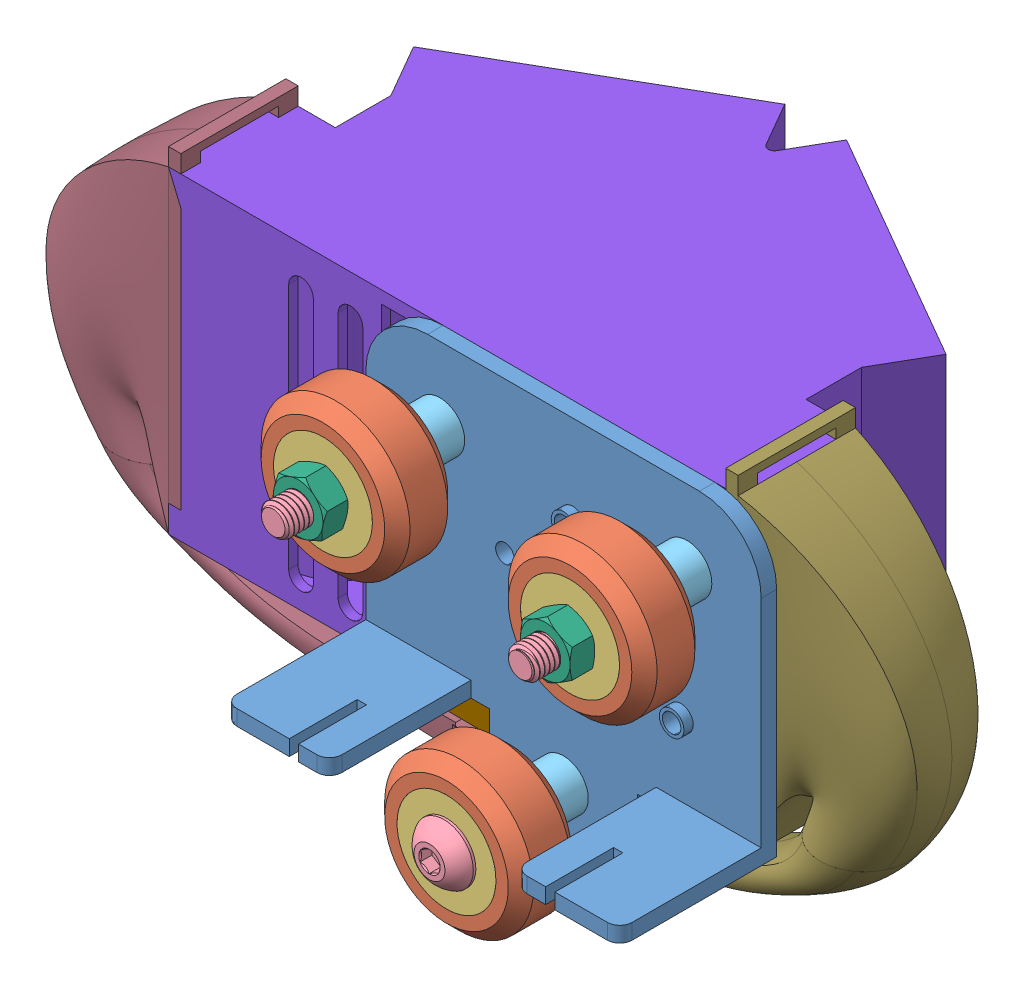
SolidWorks assembly Hot end, configuration Default. Lengths in mm.
Overall size (144.88 70.51 88.23).
31 component instances, 13 part files, 20 mates.
Components (placement in the parent):
- extruder_x_assembly-1: extruder_x_assembly [Default] at origin size (67.79 70.29 37.68)
  - E-Plate (Hot end plate)-1: E-Plate (Hot end plate) [Default] at origin size (64 64.1 29.9)
  - roller_screw_assembly-4: roller_screw_assembly [2.5mm_gap] at (20 11.85 15.1) x (-1 0 0) z (0 0 -1) size (24.1 24.1 32.32)
    - roller_rubber-1: roller_rubber [Default] at origin size (24.1 24.1 10.2)
    - Bearing for Roller-1: Bearing for Roller [Default] at (0 0 3.1) x (0.970422 -0.241413 0) z (0 0 1) size (16 16 2)
    - Bearing for Roller-2: Bearing for Roller [Default] at (0 0 -5.1) x (0.995973 0.089651 0) z (0 0 1) size (16 16 2)
    - 92095A211_Button Head Hex Drive Screw-1: 92095A211_Button Head Hex Drive Screw [92095A211] at (0 0 19.1) x (-0.966026 0.258445 0) z (0 0 1) size (9.5 9.5 32.49)
    - Roller Spacer-1: Roller Spacer [long] at (0 0 5.1) x (0.816952 -0.576706 0) z (0 0 1) size (8 8 8.75)
  - roller_screw_assembly-5: roller_screw_assembly [2.5mm_gap] at (-20 11.85 15.1) x (0.382683 -0.92388 0) z (0 0 -1) size (24.1 24.1 32.32)
    - roller_rubber-1: roller_rubber [Default] at origin size (24.1 24.1 10.2)
    - Bearing for Roller-1: Bearing for Roller [Default] at (0 0 3.1) x (0.970422 -0.241413 0) z (0 0 1) size (16 16 2)
    - Bearing for Roller-2: Bearing for Roller [Default] at (0 0 -5.1) x (0.995973 0.089651 0) z (0 0 1) size (16 16 2)
    - 92095A211_Button Head Hex Drive Screw-1: 92095A211_Button Head Hex Drive Screw [92095A211] at (0 0 19.1) x (-0.966026 0.258445 0) z (0 0 1) size (9.5 9.5 32.49)
    - Roller Spacer-1: Roller Spacer [long] at (0 0 5.1) x (0.816952 -0.576706 0) z (0 0 1) size (8 8 8.75)
  - roller_screw_assembly-6: roller_screw_assembly [normal] at (0 -28.35 15.1) x (0.97681 0.214109 0) z (0 0 1) size (24.1 24.1 32.32)
    - roller_rubber-1: roller_rubber [Default] at origin size (24.1 24.1 10.2)
    - Bearing for Roller-1: Bearing for Roller [Default] at (0 0 3.1) x (0.970422 -0.241413 0) z (0 0 1) size (16 16 2)
    - Bearing for Roller-2: Bearing for Roller [Default] at (0 0 -5.1) x (0.995973 0.089651 0) z (0 0 1) size (16 16 2)
    - 92095A211_Button Head Hex Drive Screw-1: 92095A211_Button Head Hex Drive Screw [92095A211] at (0 0 7.85) x (-0.966026 0.258445 0) z (0 0 1) size (9.5 9.5 32.49)
    - Roller Spacer-1: Roller Spacer [long] at (0 0 -13.85) x (0.816952 -0.576706 0) z (0 0 1) size (8 8 8.75)
  - 91828A241_18-8 Stainless Steel Hex Nut-4: 91828A241_18-8 Stainless Steel Hex Nut [91828A241] at (0 -28.35 -3.25) x (0.27421 -0.96167 0) z (0 0 1) size (8 9.24 4.46)
  - 91828A241_18-8 Stainless Steel Hex Nut-5: 91828A241_18-8 Stainless Steel Hex Nut [91828A241] at (20 11.85 22.2) size (8 9.24 4.46)
  - 91828A241_18-8 Stainless Steel Hex Nut-6: 91828A241_18-8 Stainless Steel Hex Nut [91828A241] at (-20 11.85 22.2) x (0.983363 -0.181649 0) z (0 0 1) size (8 9.24 4.46)
- radiator-1: radiator [Default] at (-16.5 -10.6 -11.75) size (20 27.8 12.17)
- blower-1: blower [Default] at (-20.3443 -2 -26.25) x (-1 0 0) z (0 0 -1) size (92.21 51.5 58.66)
- heatBlock-1: heatBlock [Default] at (-16.4651 -24.5 -15.7498) x (-0.999962 0 -0.008727) z (0.008727 0 -0.999962) size (20 10 20)
- nozzle-1: nozzle [Default] at (-16.5 -43.5 -11.75) x (1 0 0.000361) z (-0.000361 0 1) size (7.5 12.42 6)
- 40mm_10mm_fan-1: 40mm_10mm_fan [1939K43] at (3.4402 -5.75 -49.065) x (0.866025 0 0.5) z (-0.5 0 0.866025) size (40 40 10.64)
- 40mm_10mm_fan-2: 40mm_10mm_fan [1939K43] at (-44.3969 -5.75 -48.9103) x (0.866025 0 -0.5) z (0.5 0 0.866025) size (40 40 10.64)
- loftTesrtleft-1: loftTesrtleft [Default] at (23.7607 -39.3943 -10.75) x (0 0 1) z (-1 0 0) size (19 68.5 60.72)
- loftTesrtRight-1: loftTesrtRight [Default] at (-64.4493 -39.3943 -10.75) x (0 0 -1) z (1 0 0) size (19 68.5 68.32)
Mates (geometry in assembly coordinates):
- Coincident1: coincident anti-aligned: plane of extruder_x_assembly-1/E-Plate (Hot end plate)-1 through (-23.5 -0.7 -5.75) normal (0 0 -1); plane of radiator-1 through (-16.5 -10.6 -5.75) normal (0 0 1)
- Concentric1: concentric aligned: cylinder of extruder_x_assembly-1/E-Plate (Hot end plate)-1 through (-23.5 -0.7 -5.75) axis (0 0 1) radius 2.7; cylinder of radiator-1 through (-23.5 -0.7 -17.75) axis (0 0 1) radius 1.3539
- Concentric2: concentric aligned: cylinder of extruder_x_assembly-1/E-Plate (Hot end plate)-1 through (-9.5 -0.7 -5.75) axis (0 0 1) radius 2.7; cylinder of radiator-1 through (-9.5 -0.7 -17.75) axis (0 0 1) radius 1.3539
- Coincident6: coincident anti-aligned: plane of extruder_x_assembly-1/E-Plate (Hot end plate)-1 through (0 -28.35 -1.25) normal (0 0 -1); plane of blower-1 through (-20.3443 -2 -1.25) normal (0 0 1)
- Coincident7: coincident aligned: plane of extruder_x_assembly-1/E-Plate (Hot end plate)-1 through (-32 23.75 1.25) normal (0 1 0); plane of blower-1 through (17.7607 23.75 -51.25) normal (0 1 0)
- Coincident10: coincident anti-aligned: plane of extruder_x_assembly-1/E-Plate (Hot end plate)-1 through (-32 23.75 1.25) normal (-1 0 0); plane of blower-1 through (-32 -27.75 -1.25) normal (1 0 0)
- Concentric4: concentric aligned: cylinder of radiator-1 through (-16.5 -24.5 -11.75) axis (0 1 0) radius 3.5; cylinder of heatBlock-1 through (-16.5 -34.5 -11.75) axis (0 1 0) radius 3
- Coincident11: coincident anti-aligned: plane of radiator-1 through (-6.5 -24.5 -17.75) normal (0 -1 0); plane of heatBlock-1 through (-16.4651 -24.5 -15.7498) normal (0 1 0)
- Concentric5: concentric anti-aligned: cylinder of heatBlock-1 through (-16.5 -34.5 -11.75) axis (0 1 0) radius 3; cylinder of nozzle-1 through (-16.5 -30.5 -11.75) axis (0 -1 0) radius 3
- Distance1: distance = 4 mm anti-aligned: plane of nozzle-1 through (-16.5 -30.5 -11.75) normal (0 1 0); plane of heatBlock-1 through (-16.4651 -34.5 -15.7498) normal (0 -1 0)
- Coincident13: coincident anti-aligned: plane of blower-1 through (17.7607 -25.75 -51.25) normal (0 1 0); plane of 40mm_10mm_fan-1 through (-43.7005 -25.75 0.585) normal (0 -1 0)
- Coincident14: coincident anti-aligned: plane of blower-1 through (20.7607 21.75 -39.065) normal (-0.866025 0 -0.5); plane of 40mm_10mm_fan-1 through (-12.5236 -21.75 18.585) normal (0.866025 0 0.5)
- Coincident15: coincident aligned: plane of blower-1 through (-4.519 -2 -53.6603) normal (0.5 0 -0.866025); plane of 40mm_10mm_fan-1 through (17.2966 -21.75 -41.065) normal (0.5 0 -0.866025)
- Coincident16: coincident anti-aligned: plane of blower-1 through (-27.0764 21.75 -58.9103) normal (-0.866025 0 0.5); plane of 40mm_10mm_fan-2 through (6.2079 -21.75 -1.2602) normal (0.866025 0 -0.5)
- Coincident17: coincident anti-aligned: plane of blower-1 through (17.7607 -25.75 -51.25) normal (0 1 0); plane of 40mm_10mm_fan-2 through (-24.969 -25.75 16.7398) normal (0 -1 0)
- Coincident18: coincident aligned: plane of blower-1 through (-36.1696 -2 -53.6603) normal (-0.5 0 -0.866025); plane of 40mm_10mm_fan-2 through (-30.5405 -21.75 -56.9103) normal (-0.5 0 -0.866025)
- Coincident23: coincident anti-aligned: line of blower-1 through (25.7607 23.75 -20.25) axis (0 0 1); line of loftTesrtleft-1 through (25.7607 23.75 -1.25) axis (0 0 -1)
- Coincident24: coincident anti-aligned: line of blower-1 through (25.7607 -27.75 -20.25) axis (0 1 0); line of loftTesrtleft-1 through (25.7607 23.75 -20.25) axis (0 -1 0)
- Coincident25: coincident anti-aligned: line of blower-1 through (-66.4493 23.75 -20.25) axis (0 0 1); line of loftTesrtRight-1 through (-66.4493 23.75 -10.75) axis (0 0 -1)
- Coincident26: coincident anti-aligned: line of blower-1 through (-66.4493 23.75 -1.25) axis (0 -1 0); line of loftTesrtRight-1 through (-66.4493 -27.75 -1.25) axis (0 1 0)
